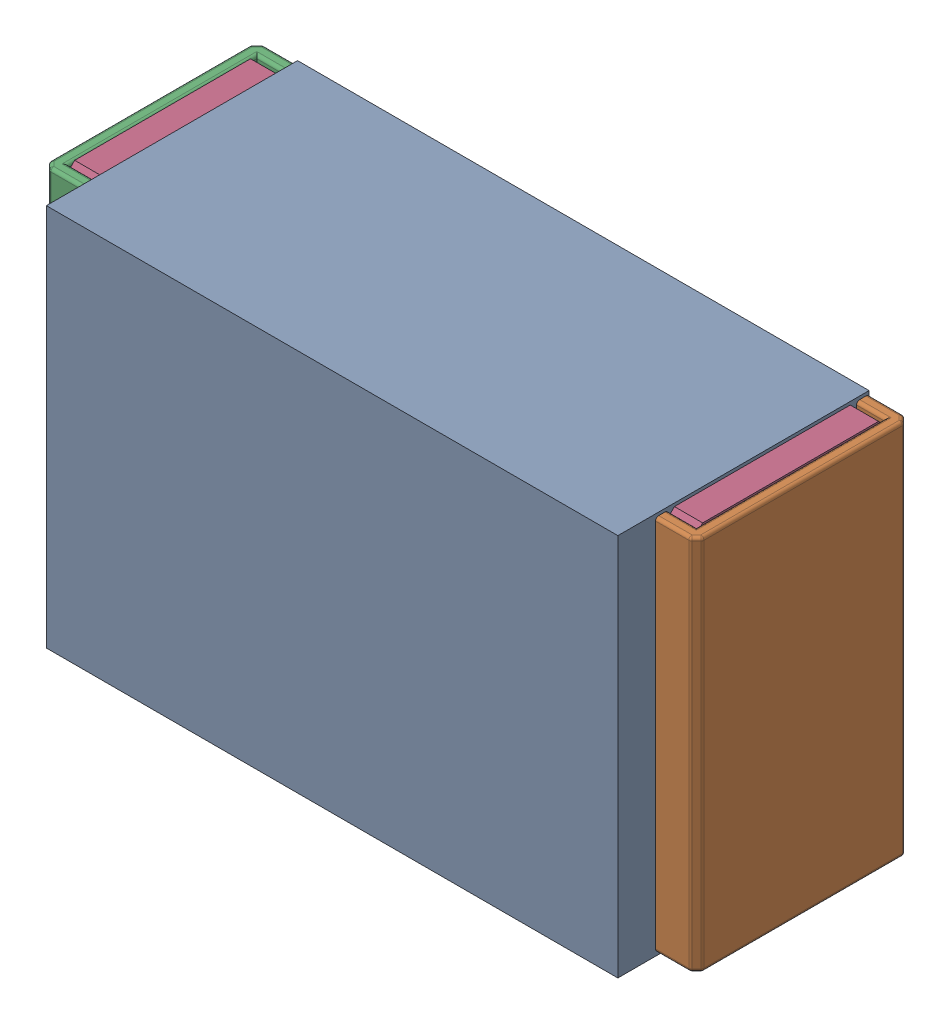
SolidWorks assembly R3, configuration Default. Lengths in mm.
Overall size (1.04 0.61 0.4).
3 component instances, 2 part files, 0 mates.
Components (placement in the parent):
- 1088880352-1: 1088880352 [Default] at (4.6 41.925 0) size (0.91 0.61 0.4)
  - Extruded-28-1: Extruded-28 [Default] at origin size (0.91 0.61 0.4)
- R0402-1: R0402 [Default] at (4.6001 41.925 0) x (1 0 0) z (0 -1 0) size (1.04 0.34 0.6)
